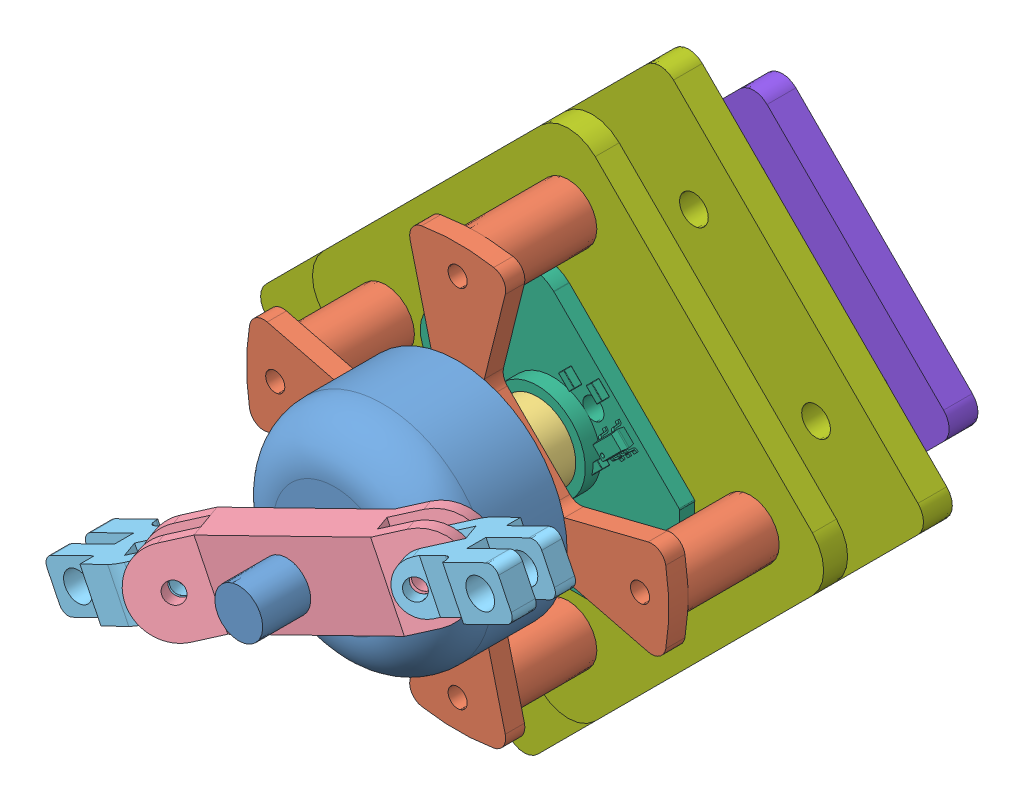
SolidWorks assembly 电机装配体, configuration 默认. Lengths in mm.
Overall size (70.71 70.71 51.74).
9 component instances, 8 part files, 18 mates.
Components (placement in the parent):
- 1804无刷电机-1: 1804无刷电机 [默认] at (-31.4232 5.8693 -20.2732) size (22.8 22.8 24.3)
- 电机固定-1: 电机固定 [默认] at (-31.4232 5.8693 -22.2732) size (44 44 11.5)
- 磁铁安装件-1: 磁铁安装件 [默认] at (-31.4232 5.8693 -25.3055) x (-0.923728 -0.383049 0) z (0 0 -1) size (8 8 8)
- 旋翼铰链2_电机端-1: 旋翼铰链2_电机端 [默认] at (-31.4232 5.8693 -7.4732) x (0.898144 0.439701 0) z (0.439701 -0.898144 0) size (35.5 12 8)
- 旋翼固定3-1: 旋翼固定3 [默认] at (-43.0512 0.1766 -2.3751) x (-0.777816 -0.380792 0.5) z (-0.449072 -0.21985 -0.866025) size (14.76 5 12.01)
- 旋翼固定3-2: 旋翼固定3 [默认] at (-19.7952 11.5619 -7.5713) x (0.777816 0.380792 -0.5) z (0.449072 0.21985 0.866025) size (14.76 5 12.01)
- as5047-1: as5047 [默认] at (-59.2839 -135.6815 -30.1732) x (0.707107 0.707107 0) z (0 0 1) size (18.25 24.43 4.25)
- 底座-1: 底座 [默认] at (-4.4632 -30.8991 -34.2732) x (0.707107 -0.707107 0) z (0 0 1) size (40 60 5.5)
- 测试架固定_底-1: 测试架固定_底 [默认] at (-31.4232 5.8693 -40.4822) x (-0.707107 -0.707107 0) z (0.707107 -0.707107 0) size (60 7 30)
Mates (geometry in assembly coordinates):
- 同心2: concentric: circle of assembly; circle of assembly; circle of 1804无刷电机-1; circle of 电机固定-1
- 重合1: coincident: plane of assembly; plane of assembly; plane of 1804无刷电机-1 through (-31.4232 5.8693 -20.2732) normal (0 0 -1); plane of 电机固定-1 through (-31.4232 5.8693 -20.2732) normal (0 0 1)
- 同心3: concentric: circle of assembly; circle of assembly; circle of 1804无刷电机-1; circle of 磁铁安装件-1
- 重合2: coincident: plane of assembly; plane of assembly; plane of 1804无刷电机-1 through (-31.4232 5.8693 -7.4732) normal (0 0 1); plane of 旋翼铰链2_电机端-1 through (-31.4232 5.8693 -7.4732) normal (0 0 -1)
- 同心4: concentric: circle of assembly; circle of assembly; circle of 1804无刷电机-1; circle of 旋翼铰链2_电机端-1
- 同心6: concentric: circle of assembly; circle of assembly; circle of 旋翼铰链2_电机端-1; circle of 旋翼固定3-1
- 同心7: concentric: circle of assembly; circle of assembly; circle of 旋翼铰链2_电机端-1; circle of 旋翼固定3-2
- 同心8: concentric: circle of assembly; circle of assembly; circle of 磁铁安装件-1; circle of as5047-1
- 平行1: parallel: plane of assembly; plane of as5047-1 through (-44.2162 5.7024 -31.7732) normal (-0.707107 -0.707107 0); line of assembly
- 重合4: coincident: plane of assembly; plane of assembly; plane of 电机固定-1 through (-31.4232 -13.1307 -31.7732) normal (0 0 -1); plane of as5047-1 through (-31.0518 -7.2923 -31.7732) normal (0 0 -1)
- 同心10: concentric: circle of assembly; circle of assembly; circle of as5047-1; circle of 底座-1
- 平行3: parallel: plane of assembly; plane of 底座-1 through (-31.4232 -22.415 -31.7732) normal (-0.707107 -0.707107 0); line of assembly
- 重合9: coincident: plane of assembly; plane of assembly; plane of 电机固定-1 through (-31.4232 24.8693 -31.7732) normal (0 0 -1); plane of 底座-1 through (-4.4632 -30.8991 -31.7732) normal (0 0 1)
- 重合10: coincident: plane of assembly; plane of assembly; plane of 旋翼铰链2_电机端-1 through (-31.4232 5.8693 -4.9732) normal (0 0 1); plane of 旋翼固定3-2 through (-19.7952 11.5619 -4.9732) normal (0 0 1)
- 重合11: coincident: plane of assembly; plane of assembly; plane of 旋翼铰链2_电机端-1 through (-31.4232 5.8693 -4.9732) normal (0 0 1); plane of 旋翼固定3-1 through (-43.0512 0.1766 -4.9732) normal (0 0 -1)
- 平行4: parallel: plane of assembly; plane of assembly; plane of 电机固定-1 through (-31.4232 5.8693 -20.2732) normal (0 0 1); plane of 测试架固定_底-1 through (-31.4232 5.8693 -40.4822) normal (0 0 1)
- 同心11: concentric: circle of assembly; circle of assembly; circle of as5047-1; circle of 测试架固定_底-1
- 平行5: parallel: plane of assembly; plane of assembly; plane of 底座-1 through (-31.4232 34.1535 -31.7732) normal (-0.707107 0.707107 0); plane of 测试架固定_底-1 through (-63.243 -4.7373 -43.4822) normal (-0.707107 0.707107 0)
